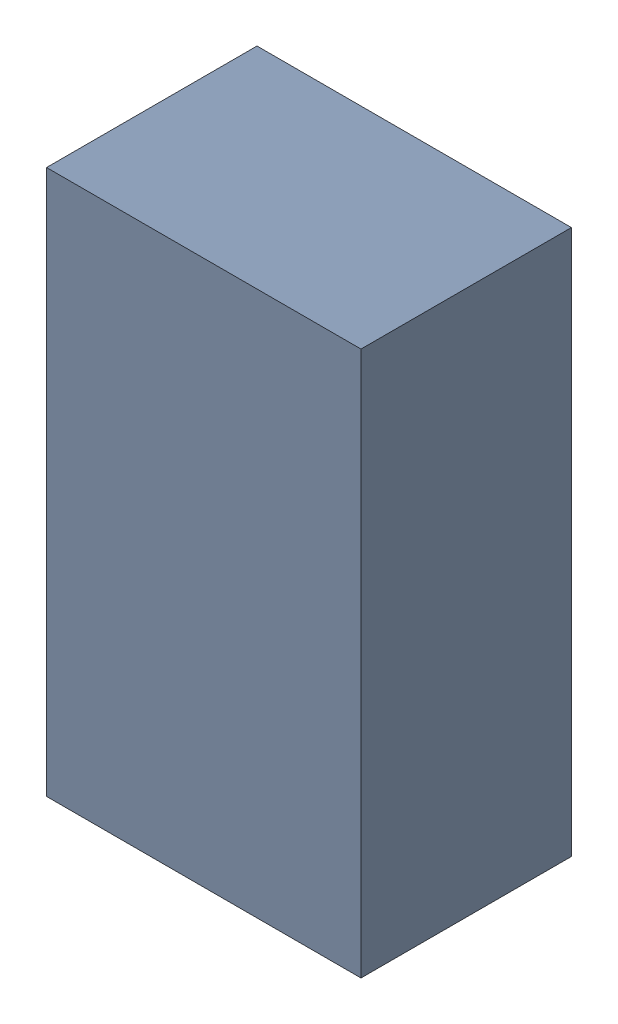
SolidWorks assembly U8Kanaloa_v2.0.0_Motor, configuration Default. Lengths in mm.
Overall size (1.27 2.2 0.85).
2 component instances, 1 part files, 0 mates.
Components (placement in the parent):
- 334788272-1: 334788272 [Default] at (130.556 108.966 -3.7524) size (1.27 2.2 0.85)
  - Extruded_16-1: Extruded_16 [Default] at origin size (1.27 2.2 0.85)
